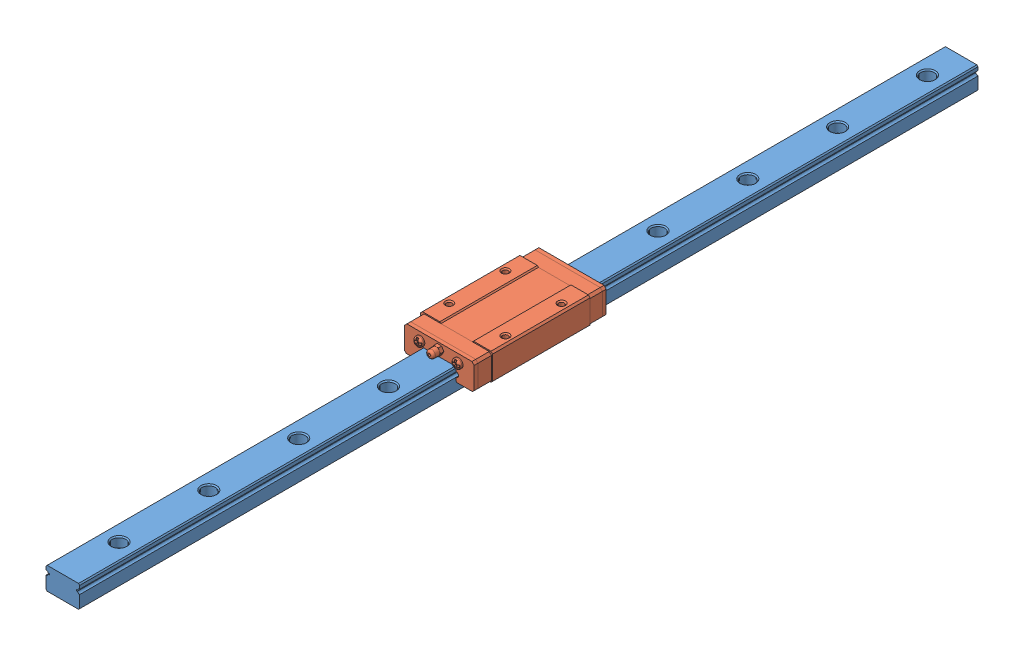
SolidWorks assembly MGN15H-400, configuration 預設. Lengths in mm.
Overall size (32 16 400).
2 component instances, 2 part files, 3 mates.
Components (placement in the parent):
- MGNR15 400mm-1: MGNR15 400mm [Default] at origin size (15 10 400)
- MGN15H-1: MGN15H [Default] at (0 0 181.2355) size (32 12 64.87)
Mates (geometry in assembly coordinates):
- 同軸心1: concentric: cylinder of MGN15H-1 through (7.5 7 226.8355) axis (0 0 -1) radius 1.0308; cylinder of MGNR15 400mm-1 through (7.5 7 400) axis (0 0 -1) radius 1.0308
- 同軸心2: concentric: cylinder of MGN15H-1 through (-7.5 7 226.8355) axis (0 0 -1) radius 1.0308; cylinder of MGNR15 400mm-1 through (-7.5 7 400) axis (0 0 -1) radius 1.0308
- 重合/共線/共點3: coordinate: point of MGNR15 400mm-1
